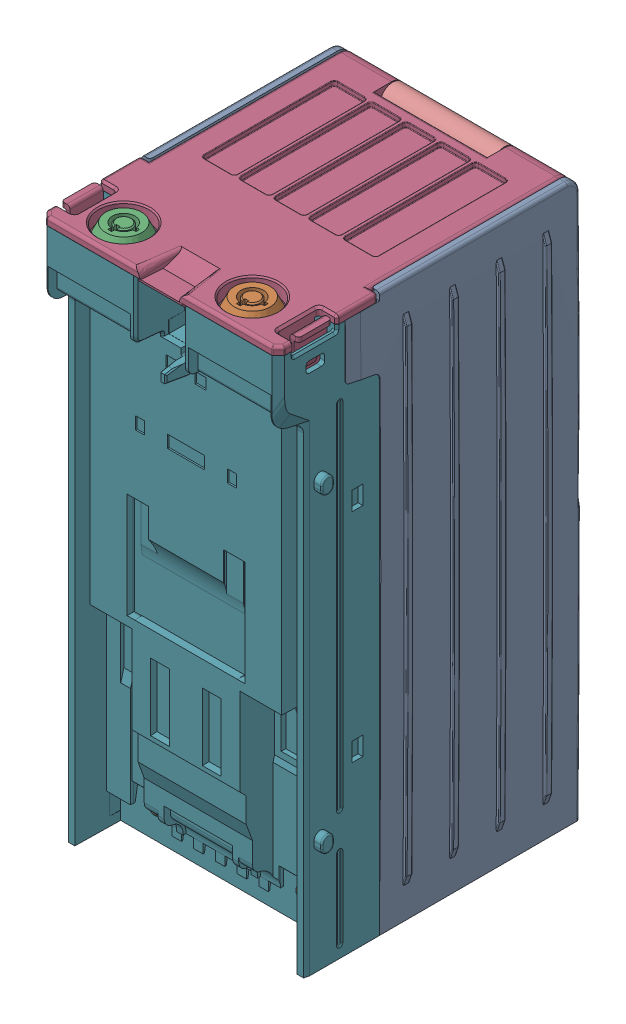
SolidWorks assembly ASY-M-101325 Casbox Assy, 300-1, configuration Default. Lengths in mm.
Overall size (81.5 180.71 97.38).
12 component instances, 5 part files, 0 mates.
Components (placement in the parent):
- Note Cashbox-1-1: Note Cashbox-1 [Default] at (0 0.1 26.25) size (79.39 180.47 75.3)
  - ASY-M-601299 R10.1 CashBox Cover, 300-1-1: ASY-M-601299 R10.1 CashBox Cover, 300-1 [Default] at origin size (79.39 180.47 75.3)
- ASY-M-111326 Lid, Cashbox Assy-1-1: ASY-M-111326 Lid, Cashbox Assy-1 [Default] at origin size (76.59 15.65 97.24)
  - Lock Assy(Default)-2-1: Lock Assy(Default)-2 [Default] at (19.2 81.5 11.8443) x (0 0 1) z (0 1 0) size (15 15 15.5)
    - Lock - 10220022001-2-1: Lock - 10220022001-2 [Default] at (0 0 7.5) x (-1 0 0) z (0 0 -1) size (15 15 15.5)
      - Lock Body - 10220022001-2-1: Lock Body - 10220022001-2 [Default] x (-1 0 0) z (0 0 1) size (15 15 15.5)
  - Lock Assy(Default)-1-2-1: Lock Assy(Default)-1-2 [Default] at (-22.2 81.5 11.8443) x (0 0 1) z (0 1 0) size (15 15 15.5)
    - Lock - 10220022001-1-2-1: Lock - 10220022001-1-2 [Default] at (0 0 7.5) x (-1 0 0) z (0 0 -1) size (15 15 15.5)
      - Lock Body - 10220022001-2-1: Lock Body - 10220022001-2 [Default] x (-1 0 0) z (0 0 1) size (15 15 15.5)
  - ASY-M-601303 R6.2 Lid, CashBox-2-1: ASY-M-601303 R6.2 Lid, CashBox-2 [Default] at origin size (76.59 15.65 97.24)
- ASY-M-601298 R9.1 Stacker Base(Default)-2-1: ASY-M-601298 R9.1 Stacker Base(Default)-2 [Default] at origin size (81.5 177 34.34)
- ASY-M-601304 R3.1 LID,BACK CASSETTE-1-1: ASY-M-601304 R3.1 LID,BACK CASSETTE-1 [Default] at (0 48 -69.55) x (0 -1 0) z (1 0 0) size (48.3 16 70.82)
